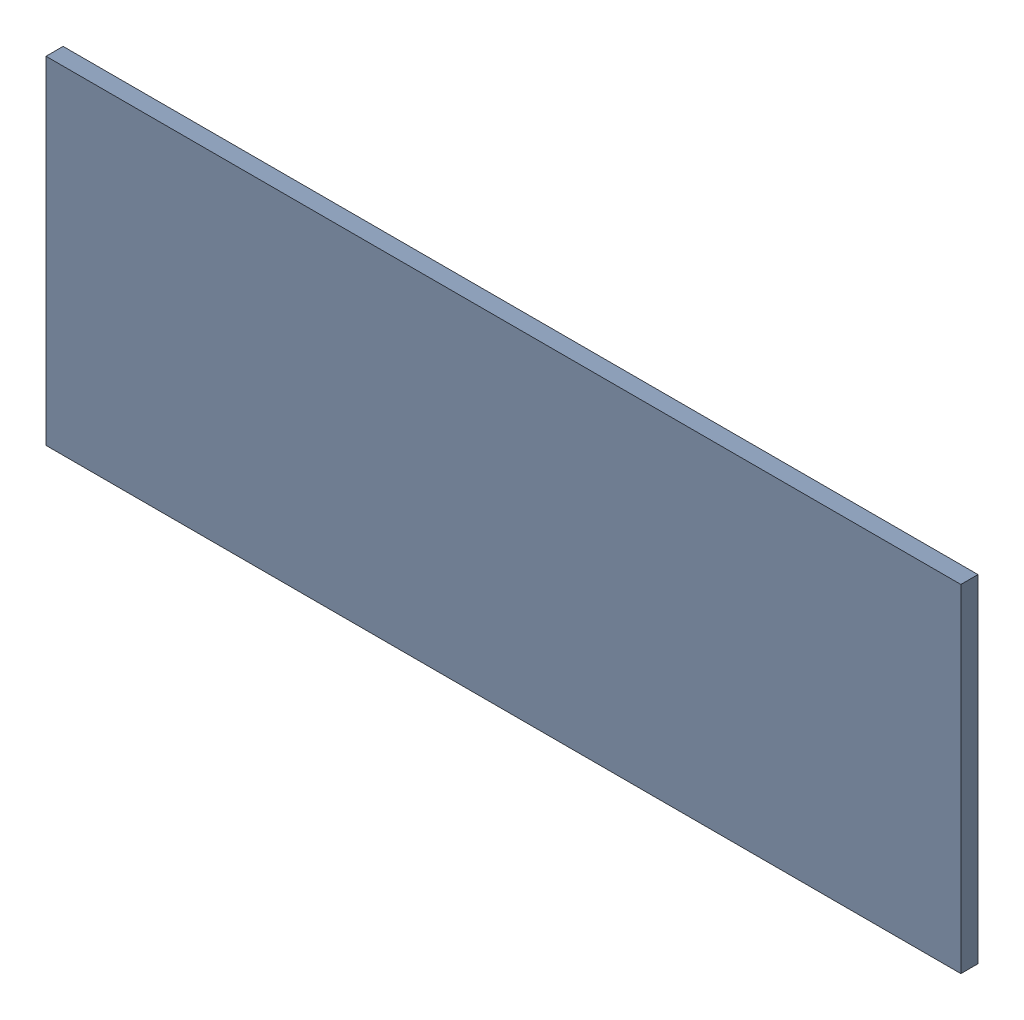
SolidWorks assembly Pad RAK4600-4(14.5mm,23.75mm) on Top Layer, configuration Predeterminado. Lengths in mm.
Overall size (1.9 0.7 0.04).
2 component instances, 1 part files, 0 mates.
Components (placement in the parent):
- Pad RAK4600-4(14.5mm,23.75mm) on Top Layer-1-1: Pad RAK4600-4(14.5mm,23.75mm) on Top Layer-1 [Predeterminado] at (-68.317 -44.187 -0.0457) size (1.9 0.7 0.04)
  - Pad RAK4600-4(14.5mm,23.75mm) on Top Layer-Part-1-1: Pad RAK4600-4(14.5mm,23.75mm) on Top Layer-Part-1 [Predeterminado] at origin size (1.9 0.7 0.04)
